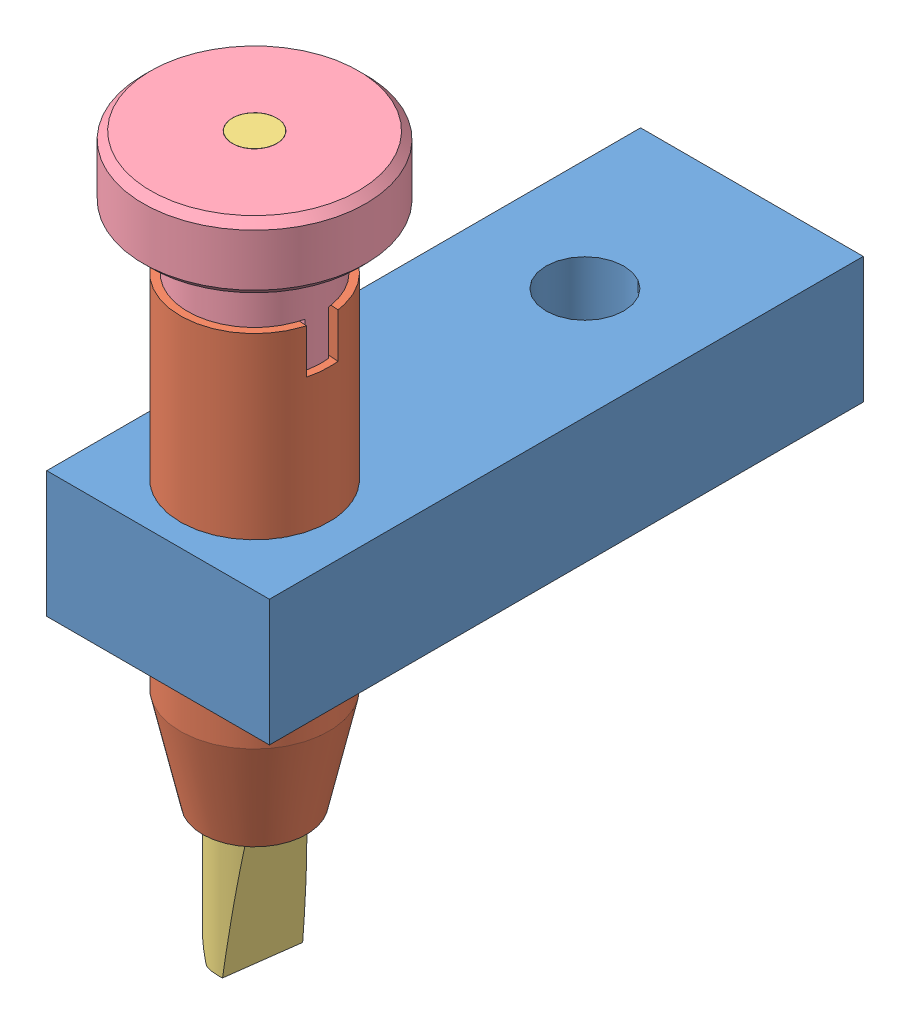
SolidWorks assembly doigt immobilisation diviseur CG, configuration Défaut. Lengths in mm.
Overall size (31.61 96.07 82.8).
4 component instances, 4 part files, 3 mates.
Components (placement in the parent):
- support1-1: support1 [Défaut] at (-44.8451 12.9883 -40) size (30 22 80)
- support2-1: support2 [Défaut] at (-59.8451 54.0452 27) x (0 -1 0) z (0.068511 0 -0.99765) size (62 20 20)
- doigt-1: doigt [Défaut] at (-59.8451 70.5753 27) x (0.991579 0 0.129506) z (0 -1 0) size (9.56 9.95 96.07)
- molette-1: molette [Défaut] at (-59.8451 70.6396 27) x (0 -1 0) z (-0.055148 0 0.998478) size (22.8 30 30)
Mates (geometry in assembly coordinates):
- Coaxiale2: concentric aligned: cylinder of support1-1 through (-59.8451 7.9883 27) axis (0 1 0) radius 10; cylinder of support2-1 through (-59.8451 91.0299 27) axis (0 1 0) radius 10
- Coaxiale3: concentric aligned: cylinder of support2-1 through (-59.8451 91.0299 27) axis (0 1 0) radius 3; cylinder of doigt-1 through (-59.8451 70.6454 27) axis (0 1 0) radius 2.98
- Coaxiale4: concentric aligned: cylinder of doigt-1 through (-59.8451 70.6454 27) axis (0 1 0) radius 2.98; cylinder of molette-1 through (-59.8451 85.3421 27) axis (0 1 0) radius 3
